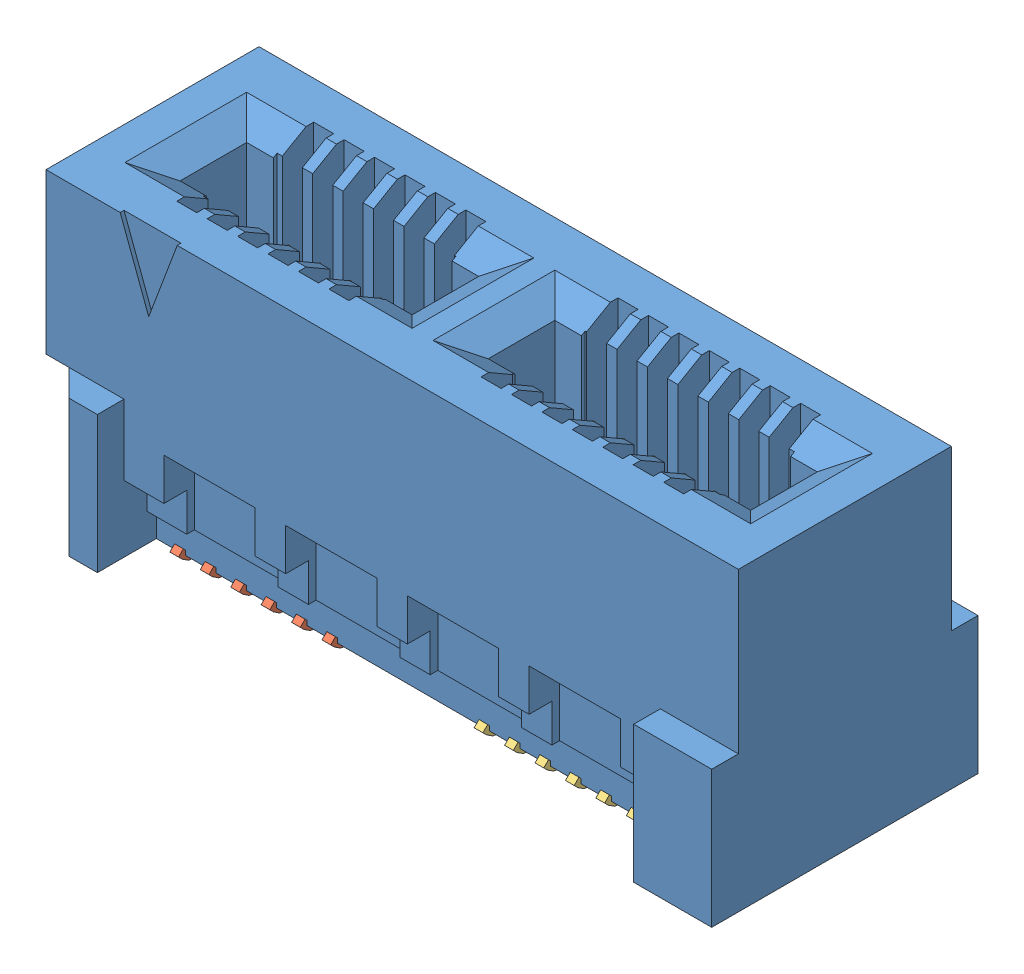
SolidWorks assembly HSEC8_113_01_L_DV, configuration Default. Lengths in mm.
Overall size (18.2 7.98 7).
3 component instances, 3 part files, 0 mates.
Components (placement in the parent):
- _HSEC8_113_01_L_DVter_2-1: _HSEC8_113_01_L_DVter_2 [Default] at origin size (18.2 7.8 7)
- _C_188_02_Pin_6_01_4-1: _C_188_02_Pin_6_01_4 [Default] at (-6.4 -0.183 0) x (0 0 1) z (-1 0 0) size (4.26 5.75 4.58)
- _C_188_02_Pin_7_01_6-1: _C_188_02_Pin_7_01_6 [Default] at (1.6 -0.183 0) x (0 0 1) z (-1 0 0) size (4.26 5.75 5.38)
